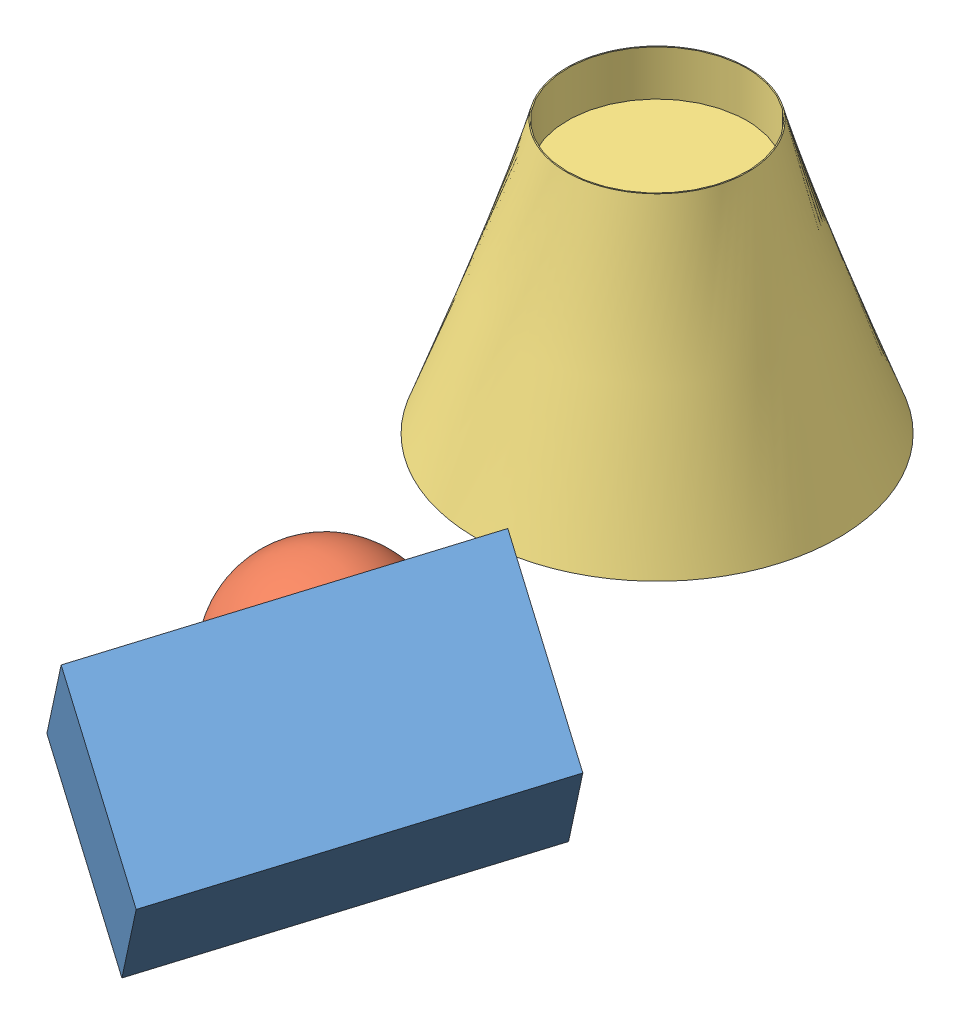
SolidWorks assembly Assem1, configuration Default. Lengths in mm.
Overall size (178.34 171.77 219.91).
3 component instances, 3 part files, 0 mates.
Components (placement in the parent):
- torso-1: torso [Default] at (125.1091 23.8451 -28.8864) x (0.562679 0.619742 0.547095) z (-0.541758 -0.223434 0.810293) size (202.29 40 72.99)
- sphere joint-2: sphere joint [Default] at (110.1002 53.1568 -37.8637) size (40 40 40)
- cone-1: cone [Default] at (99.8827 49.5288 -121.4399) size (83.57 60 84.89)
